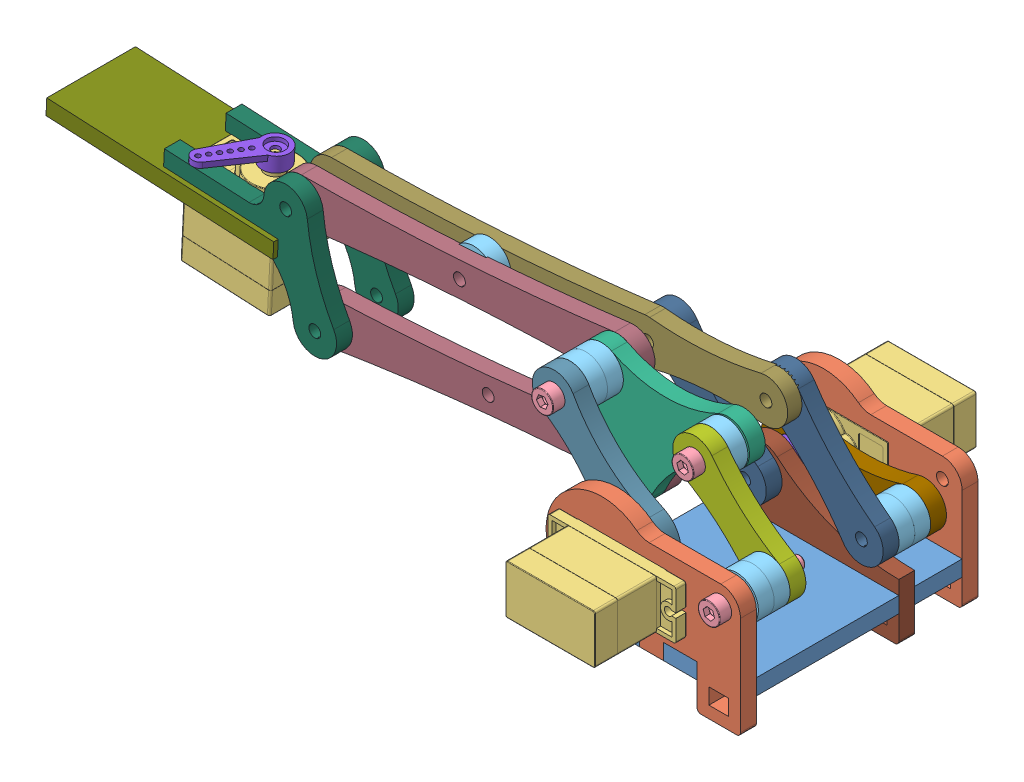
SolidWorks assembly Arm, configuration Default. Lengths in mm.
Overall size (197.53 59.85 96.4).
33 component instances, 16 part files, 77 mates.
Components (placement in the parent):
- Base (Finger Joint Connection)-1: Base (Finger Joint Connection) [Default] at (25.9477 4 37.3679) x (1 0 0) z (0 -1 0) size (45 60 4)
- Side Panel (Finger Joint Connection)-1: Side Panel (Finger Joint Connection) [Default] at (25.9477 4 93.3679) size (49.14 35.14 4)
- Side Panel (Finger Joint Connection)-2: Side Panel (Finger Joint Connection) [Default] at (25.9477 4 37.3679) size (49.14 35.14 4)
- microservoSG90-3: microservoSG90 [Default] at (41.0477 14 19.1679) x (1 0 0) z (0 -1 0) size (32.3 29.8 12.5)
- socket head cap screw_iso-3: socket head cap screw_iso [ISO 4762 M3 x 20 - 20N] at (65.9477 19 100.3679) x (0 0 -1) z (0.947312 0.320314 0) size (23 5.5 5.5)
- 4mm Spacer-2: 4mm Spacer [Default] at (65.9477 19 93.3679) x (0.6336 -0.773661 0) z (0.773661 0.6336 0) size (11 4 11)
- Stabilizer Triangle-1: Stabilizer Triangle [Default] at (22.5845 15.5383 72.9679) x (0.943404 0.331646 0) z (0 0 1) size (41 32.57 4)
- 4mm Spacer-3: 4mm Spacer [Default] at (15.4309 35.8875 84.9679) x (-0.98853 -0.151025 0) z (0.151025 -0.98853 0) size (11 4 11)
- socket head cap screw_iso-4: socket head cap screw_iso [ISO 4762 M3 x 16 - 16N] at (15.4309 35.8875 91.9679) x (0 0 -1) z (0.778189 0.62803 0) size (19 5.5 5.5)
- X-Link-1: X-Link [Default] at (65.9477 19 81.3679) x (0.666489 0.745515 0) z (0.745515 -0.666489 0) size (11 4 36)
- 4mm Spacer-4: 4mm Spacer [Default] at (65.9477 19 89.3679) x (0.6336 -0.773661 0) z (0.773661 0.6336 0) size (11 4 11)
- SG90 - Micro Servo 9g - Tower Pro.2-1: SG90 - Micro Servo 9g - Tower Pro.2 [Peça] at (35.9477 14 83.5679) x (0.767364 -0.641212 0) z (0.641212 0.767364 0) size (19.5 3.8 6.9)
- socket head cap screw_iso-5: socket head cap screw_iso [ISO 4762 M3 x 12 - 12N] at (47.3098 35.6622 88.3679) x (0 0 -1) z (0.947312 0.320314 0) size (15 5.5 5.5)
- 4mm Spacer-5: 4mm Spacer [Default] at (15.4309 35.8875 80.9679) x (0.983445 -0.181209 0) z (0.181209 0.983445 0) size (11 4 11)
- 4mm Spacer-6: 4mm Spacer [Default] at (47.3098 35.6622 81.3679) x (0.937465 0.34808 0) z (-0.34808 0.937465 0) size (11 4 11)
- Y-Servo Link-1: Y-Servo Link [Default] at (50.9155 14.982 45.7679) x (0.065468 -0.997855 0) z (0 0 1) size (15.2 43.1 4)
- Y-Link 1-1: Y-Link 1 [Default] at (65.8833 15.964 57.7679) x (0.729583 0.683893 0) z (0.683893 -0.729583 0) size (11 4 41)
- SG90 - Micro Servo 9g - Tower Pro.2-2: SG90 - Micro Servo 9g - Tower Pro.2 [Peça] at (35.9477 14 51.1679) x (-0.768689 0.639623 0) z (0.639623 0.768689 0) size (19.5 3.8 6.9)
- 4mm Spacer-7: 4mm Spacer [Default] at (65.8833 15.964 53.7679) x (0.985317 0.170736 0) z (-0.170736 0.985317 0) size (11 4 11)
- 4mm Spacer-8: 4mm Spacer [Default] at (65.8833 15.964 57.7679) x (0.265682 0.964061 0) z (-0.964061 0.265682 0) size (11 4 11)
- Centre Y link base connector-1: Centre Y link base connector [Default] at (25.9477 4 53.3679) size (45 27.5 4)
- Y-Link 1-2: Y-Link 1 [Default] at (35.9477 14 57.3679) x (0.729583 0.683893 0) z (0.683893 -0.729583 0) size (11 4 41)
- Y-long link-1: Y-long link [Default] at (45.3665 37.8515 61.3679) x (-0.065468 0.997855 0) z (0.997855 0.065468 0) size (11 4 121)
- X-long link-1: X-long link [Default] at (15.4309 35.8875 68.9679) x (-0.065468 0.997855 0) z (0.997855 0.065468 0) size (11 4 91)
- X-Servo Link-3: X-Servo Link [Default] at (25.6893 24.9437 84.9679) x (0.729583 0.683893 0) z (0 0 1) size (15.2 43.1 4)
- microservoSG90-4: microservoSG90 [Default] at (41.0477 14 115.5679) x (1 0 0) z (0 1 0) size (32.3 29.8 12.5)
- 4mm Spacer-9: 4mm Spacer [Default] at (-24.4833 33.2687 69.3679) x (-0.98853 -0.151025 0) z (0.151025 -0.98853 0) size (11 4 11)
- X-long link-2: X-long link [Default] at (22.5845 15.5383 68.9679) x (-0.098515 0.995136 0) z (0.995136 0.098515 0) size (11 4 91)
- Horizontalizer Connector-1: Horizontalizer Connector [Default] at (-64.3975 30.65 76.9679) x (-0.998775 0.049489 0) z (0 0 -1) size (44.5 33.6 4)
- Horizontalizer Connector-2: Horizontalizer Connector [Default] at (-64.3975 30.65 61.3679) x (-0.998775 0.049489 0) z (0 0 -1) size (44.5 33.6 4)
- Gripper Servo Mount-1: Gripper Servo Mount [Default] at (-71.2656 23.381 73.1014) x (-0.998775 0.049489 0) z (0 0 1) size (57.42 4 22.42)
- microservoSG90-5: microservoSG90 [Default] at (-83.6504 1.7674 66.9014) x (-0.998775 0.049489 0) z (0 0 -1) size (32.3 29.8 12.5)
- SG90 - Micro Servo 9g - Tower Pro.2-3: SG90 - Micro Servo 9g - Tower Pro.2 [Peça] at (-76.973 33.4758 66.9014) x (0.486267 -0.024095 -0.873478) z (0.872408 -0.043228 0.486863) size (19.5 3.8 6.9)
Mates (geometry in assembly coordinates):
- Coincident2: coincident anti-aligned: plane of Base (Finger Joint Connection)-1 through (25.9477 0 37.3679) normal (0 -1 0)
- Coincident3: coincident anti-aligned: plane of Base (Finger Joint Connection)-1 through (36.9477 0 37.3679) normal (-1 0 0); plane of Side Panel (Finger Joint Connection)-1 through (36.9477 4 97.3679) normal (1 0 0)
- Coincident4: coincident anti-aligned: plane of Base (Finger Joint Connection)-1 through (25.9477 4 37.3679) normal (0 1 0); plane of Side Panel (Finger Joint Connection)-1 through (25.9477 4 97.3679) normal (0 -1 0)
- Coincident5: coincident anti-aligned: line of Base (Finger Joint Connection)-1 through (36.9477 0 97.3679) axis (0 1 0); line of Side Panel (Finger Joint Connection)-1 through (36.9477 4 97.3679) axis (0 -1 0)
- Coincident6: coincident aligned: plane of Base (Finger Joint Connection)-1 through (25.9477 0 37.3679) normal (-1 0 0); plane of Side Panel (Finger Joint Connection)-2 through (25.9477 4 41.3679) normal (-1 0 0)
- Coincident7: coincident aligned: plane of Base (Finger Joint Connection)-1 through (25.9477 0 37.3679) normal (0 0 -1); plane of Side Panel (Finger Joint Connection)-2 through (25.9477 4 37.3679) normal (0 0 -1)
- Coincident9: coincident anti-aligned: line of Base (Finger Joint Connection)-1 through (45.4477 4 37.3679) axis (0 0 1); line of Side Panel (Finger Joint Connection)-2 through (45.4477 4 41.3679) axis (0 0 -1)
- Coincident14: coincident anti-aligned: plane of Side Panel (Finger Joint Connection)-2 through (25.9477 7.8 41.3679) normal (0 1 0); plane of microservoSG90-3 through (29.7477 7.8 34.7679) normal (0 -1 0)
- Coincident15: coincident anti-aligned: plane of Side Panel (Finger Joint Connection)-2 through (29.7477 4 41.3679) normal (1 0 0); plane of microservoSG90-3 through (29.7477 20.2 41.4679) normal (-1 0 0)
- Coincident18: coincident anti-aligned: plane of Side Panel (Finger Joint Connection)-2 through (25.9477 4 37.3679) normal (0 0 -1); plane of microservoSG90-3 through (41.0477 14 37.3679) normal (0 0 1)
- Concentric11: concentric anti-aligned: cylinder of Side Panel (Finger Joint Connection)-1 through (65.9477 19 97.3679) axis (0 0 -1) radius 1.5; cylinder of socket head cap screw_iso-3 through (65.9477 19 132.1179) axis (0 0 1) radius 2.75
- Coincident19: coincident anti-aligned: plane of Side Panel (Finger Joint Connection)-1 through (25.9477 4 97.3679) normal (0 0 1); plane of socket head cap screw_iso-3 through (65.0668 21.6051 97.3679) normal (0 0 -1)
- Concentric14: concentric aligned: cylinder of socket head cap screw_iso-3 through (65.9477 19 132.1179) axis (0 0 1) radius 1.5; cylinder of 4mm Spacer-2 through (65.9477 19 89.3679) axis (0 0 1) radius 1.5
- Coincident22: coincident anti-aligned: plane of Side Panel (Finger Joint Connection)-1 through (25.9477 4 93.3679) normal (0 0 -1); plane of 4mm Spacer-2 through (65.9477 19 93.3679) normal (0 0 1)
- Concentric18: concentric anti-aligned: cylinder of Stabilizer Triangle-1 through (15.4309 35.8875 76.9679) axis (0 0 -1) radius 1.5; cylinder of socket head cap screw_iso-4 through (15.4309 35.8875 123.7179) axis (0 0 1) radius 1.5
- Concentric19: concentric anti-aligned: cylinder of socket head cap screw_iso-3 through (65.9477 19 132.1179) axis (0 0 1) radius 1.5; cylinder of X-Link-1 through (65.9477 19 85.3679) axis (0 0 -1) radius 1.5
- Coincident27: coincident anti-aligned: plane of X-Link-1 through (40.6687 0.1012 85.3679) normal (0 0 1); plane of 4mm Spacer-4 through (65.9477 19 85.3679) normal (0 0 -1)
- Concentric21: concentric aligned: cylinder of socket head cap screw_iso-3 through (65.9477 19 132.1179) axis (0 0 1) radius 1.5; cylinder of 4mm Spacer-4 through (65.9477 19 85.3679) axis (0 0 1) radius 1.5
- Coincident30: coincident anti-aligned: plane of X-Link-1 through (40.6687 0.1012 85.3679) normal (0 0 1); plane of socket head cap screw_iso-5 through (46.429 38.2673 85.3679) normal (0 0 -1)
- Concentric23: concentric anti-aligned: cylinder of X-Link-1 through (47.3098 35.6622 85.3679) axis (0 0 -1) radius 1.5; cylinder of socket head cap screw_iso-5 through (47.3098 35.6622 120.1179) axis (0 0 1) radius 1.5
- Coincident33: coincident anti-aligned: circle of 4mm Spacer-3; cylinder of socket head cap screw_iso-4 through (15.4309 35.8875 123.7179) axis (0 0 1) radius 1.5
- Coincident35: coincident anti-aligned: plane of 4mm Spacer-3 through (15.4309 35.8875 80.9679) normal (0 0 -1); plane of 4mm Spacer-5 through (15.4309 35.8875 80.9679) normal (0 0 1)
- Concentric24: concentric aligned: cylinder of socket head cap screw_iso-4 through (15.4309 35.8875 123.7179) axis (0 0 1) radius 1.5; cylinder of 4mm Spacer-5 through (15.4309 35.8875 76.9679) axis (0 0 1) radius 1.5
- Coincident36: coincident anti-aligned: plane of Stabilizer Triangle-1 through (22.5845 15.5383 76.9679) normal (0 0 1); plane of 4mm Spacer-5 through (15.4309 35.8875 76.9679) normal (0 0 -1)
- Concentric25: concentric anti-aligned: cylinder of Stabilizer Triangle-1 through (47.3098 35.6622 76.9679) axis (0 0 -1) radius 1.5; cylinder of socket head cap screw_iso-5 through (47.3098 35.6622 120.1179) axis (0 0 1) radius 1.5
- Coincident37: coincident aligned: plane of 4mm Spacer-2 through (65.9477 19 89.3679) normal (0 0 -1); plane of 4mm Spacer-4
- Concentric26: concentric aligned: cylinder of socket head cap screw_iso-5 through (47.3098 35.6622 120.1179) axis (0 0 1) radius 1.5; cylinder of 4mm Spacer-6 through (47.3098 35.6622 77.3679) axis (0 0 1) radius 1.5
- Coincident38: coincident anti-aligned: plane of X-Link-1 through (40.6687 0.1012 81.3679) normal (0 0 -1); plane of 4mm Spacer-6 through (47.3098 35.6622 81.3679) normal (0 0 1)
- Concentric27: concentric aligned: cylinder of microservoSG90-3 through (35.9477 14 48.9679) axis (0 0 -1) radius 2.45; cylinder of Y-Servo Link-1 through (35.9477 14 49.7679) axis (0 0 -1) radius 3.6
- Coincident40: coincident anti-aligned: plane of microservoSG90-3 through (41.6977 14 45.7679) normal (0 0 1); plane of Y-Servo Link-1 through (50.9155 14.982 45.7679) normal (0 0 -1)
- Concentric29: concentric anti-aligned: cylinder of microservoSG90-3 through (35.9477 14 48.9679) axis (0 0 -1) radius 0.8; circle of SG90 - Micro Servo 9g - Tower Pro.2-2
- Coincident41: coincident anti-aligned: plane of Y-Servo Link-1 through (50.9155 14.982 49.7679) normal (0 0 1); plane of SG90 - Micro Servo 9g - Tower Pro.2-2 through (35.9477 14 49.7679) normal (0 0 -1)
- Tangent6: tangent anti-aligned: plane of Y-Servo Link-1; plane of SG90 - Micro Servo 9g - Tower Pro.2-2 through (39.3408 14.6241 49.7679) normal (0.680611 0.732645 0)
- Concentric30: concentric aligned: cylinder of Y-Servo Link-1 through (65.8833 15.964 49.7679) axis (0 0 -1) radius 1.5; cylinder of Y-Link 1-1 through (65.8833 15.964 61.7679) axis (0 0 -1) radius 1.5
- Concentric31: concentric anti-aligned: cylinder of Y-Link 1-1 through (65.8833 15.964 61.7679) axis (0 0 -1) radius 1.5; cylinder of 4mm Spacer-7 through (65.8833 15.964 49.7679) axis (0 0 1) radius 1.5
- Coincident43: coincident anti-aligned: plane of Y-Servo Link-1 through (50.9155 14.982 49.7679) normal (0 0 1); plane of 4mm Spacer-7 through (65.8833 15.964 49.7679) normal (0 0 -1)
- Coincident44: coincident anti-aligned: plane of 4mm Spacer-7 through (65.8833 15.964 53.7679) normal (0 0 1); plane of 4mm Spacer-8 through (65.8833 15.964 53.7679) normal (0 0 -1)
- Concentric33: concentric aligned: cylinder of 4mm Spacer-7 through (65.8833 15.964 49.7679) axis (0 0 1) radius 1.5; cylinder of 4mm Spacer-8 through (65.8833 15.964 53.7679) axis (0 0 1) radius 1.5
- Coincident45: coincident anti-aligned: plane of Y-Link 1-1 through (28.1509 -9.1255 57.7679) normal (0 0 -1); plane of 4mm Spacer-8 through (65.8833 15.964 57.7679) normal (0 0 1)
- Concentric34: concentric aligned: cylinder of Centre Y link base connector-1 through (35.9477 14 57.3679) axis (0 0 -1) radius 1.5; cylinder of Y-Link 1-2 through (35.9477 14 61.3679) axis (0 0 -1) radius 1.5
- Coincident49: coincident anti-aligned: plane of Centre Y link base connector-1 through (25.9477 4 57.3679) normal (0 0 1); plane of Y-Link 1-2 through (-1.7847 -11.0896 57.3679) normal (0 0 -1)
- Coincident51: coincident anti-aligned: plane of Y-Link 1-2 through (-1.7847 -11.0896 61.3679) normal (0 0 1); plane of Y-long link-1 through (-23.511 -287.0423 61.3679) normal (0 0 -1)
- Concentric36: concentric aligned: cylinder of Y-Link 1-2 through (15.4309 35.8875 61.3679) axis (0 0 -1) radius 1.5; cylinder of Y-long link-1 through (15.4309 35.8875 65.3679) axis (0 0 -1) radius 1.5
- Coincident52: coincident anti-aligned: circle of Y-Link 1-1; cylinder of Y-long link-1 through (45.3665 37.8515 65.3679) axis (0 0 -1) radius 1.5
- Concentric38: concentric aligned: circle of SG90 - Micro Servo 9g - Tower Pro.2-2; cylinder of Centre Y link base connector-1 through (35.9477 14 57.3679) axis (0 0 -1) radius 1.5
- Concentric39: concentric aligned: cylinder of Stabilizer Triangle-1 through (15.4309 35.8875 76.9679) axis (0 0 -1) radius 1.5; cylinder of Y-Link 1-2 through (15.4309 35.8875 61.3679) axis (0 0 -1) radius 1.5
- Coincident57: coincident anti-aligned: plane of Base (Finger Joint Connection)-1 through (25.9477 4 37.3679) normal (0 1 0); plane of Centre Y link base connector-1 through (25.9477 4 57.3679) normal (0 -1 0)
- Coincident58: coincident anti-aligned: plane of Base (Finger Joint Connection)-1 through (25.9477 0 57.3679) normal (0 0 -1); plane of Centre Y link base connector-1 through (25.9477 4 57.3679) normal (0 0 1)
- Coincident59: coincident anti-aligned: plane of Side Panel (Finger Joint Connection)-1 through (25.9477 20.2 97.3679) normal (0 -1 0); plane of microservoSG90-4 through (29.7477 20.2 99.9679) normal (0 1 0)
- Coincident60: coincident anti-aligned: plane of Side Panel (Finger Joint Connection)-1 through (29.7477 4 97.3679) normal (1 0 0); plane of microservoSG90-4 through (29.7477 7.8 93.2679) normal (-1 0 0)
- Coincident61: coincident anti-aligned: plane of Side Panel (Finger Joint Connection)-1 through (25.9477 4 97.3679) normal (0 0 1); plane of microservoSG90-4 through (41.0477 14 97.3679) normal (0 0 -1)
- Concentric44: concentric anti-aligned: cylinder of X-Servo Link-3 through (35.9477 14 88.9679) axis (0 0 -1) radius 3.6; cylinder of microservoSG90-4 through (35.9477 14 85.7679) axis (0 0 1) radius 2.45
- Coincident62: coincident anti-aligned: plane of X-Servo Link-3 through (25.6893 24.9437 88.9679) normal (0 0 1); plane of microservoSG90-4 through (41.6977 14 88.9679) normal (0 0 -1)
- Concentric45: concentric anti-aligned: cylinder of socket head cap screw_iso-4 through (15.4309 35.8875 123.7179) axis (0 0 1) radius 1.5; cylinder of X-Servo Link-3 through (15.4309 35.8875 88.9679) axis (0 0 -1) radius 1.5
- Concentric46: concentric aligned: circle of Stabilizer Triangle-1; circle of X-long link-1
- Coincident66: coincident anti-aligned: plane of 4mm Spacer-3 through (15.4309 35.8875 84.9679) normal (0 0 1); plane of X-Servo Link-3 through (25.6893 24.9437 84.9679) normal (0 0 -1)
- Coincident67: coincident anti-aligned: plane of Stabilizer Triangle-1 through (22.5845 15.5383 72.9679) normal (0 0 -1); plane of X-long link-1 through (16.4032 -284.4235 72.9679) normal (0 0 1)
- Concentric47: concentric aligned: cylinder of Y-long link-1 through (-66.342 671.2721 65.3679) axis (0 0 -1) radius 635.125; cylinder of X-long link-1 through (-66.342 671.2721 72.9679) axis (0 0 -1) radius 635.125
- Concentric48: concentric aligned: cylinder of SG90 - Micro Servo 9g - Tower Pro.2-1 through (35.9477 14 84.9679) axis (0 0 -1) radius 3.45; cylinder of X-Servo Link-3 through (35.9477 14 88.9679) axis (0 0 -1) radius 3.6
- Coincident68: coincident anti-aligned: plane of SG90 - Micro Servo 9g - Tower Pro.2-1 through (35.9477 14 84.9679) normal (0 0 1); plane of X-Servo Link-3 through (25.6893 24.9437 84.9679) normal (0 0 -1)
- Tangent7: tangent: plane of SG90 - Micro Servo 9g - Tower Pro.2-1 through (23.802 21.5466 84.9679) normal (-0.682125 -0.731236 0); circle of X-Servo Link-3
- Concentric49: concentric anti-aligned: cylinder of X-long link-1 through (-24.4833 33.2687 72.9679) axis (0 0 -1) radius 1.5; cylinder of 4mm Spacer-9 through (-24.4833 33.2687 65.3679) axis (0 0 1) radius 1.5
- Coincident70: coincident anti-aligned: plane of Y-long link-1 through (-23.511 -287.0423 65.3679) normal (0 0 1); plane of 4mm Spacer-9
- Concentric50: concentric aligned: cylinder of Stabilizer Triangle-1 through (22.5845 15.5383 76.9679) axis (0 0 -1) radius 1.5; cylinder of X-long link-2 through (22.5845 15.5383 72.9679) axis (0 0 -1) radius 1.5
- Coincident71: coincident anti-aligned: plane of Stabilizer Triangle-1 through (22.5845 15.5383 72.9679) normal (0 0 -1); plane of X-long link-2 through (34.1758 -304.5645 72.9679) normal (0 0 1)
- Coincident72: coincident anti-aligned: circle of X-long link-1; circle of Horizontalizer Connector-1
- Concentric52: concentric anti-aligned: cylinder of X-long link-2 through (-57.0263 7.6571 72.9679) axis (0 0 -1) radius 1.5; cylinder of Horizontalizer Connector-1 through (-57.0263 7.6571 72.9679) axis (0 0 1) radius 1.5
- Coincident73: coincident aligned: circle of Y-long link-1; cylinder of Horizontalizer Connector-2 through (-64.3975 30.65 57.3679) axis (0 0 1) radius 1.5
- Coincident74: coincident anti-aligned: plane of Y-long link-1 through (-23.511 -287.0423 61.3679) normal (0 0 -1); plane of Horizontalizer Connector-2 through (-64.3975 30.65 61.3679) normal (0 0 1)
- Concentric53: concentric aligned: cylinder of Horizontalizer Connector-1 through (-57.0263 7.6571 72.9679) axis (0 0 1) radius 1.5; cylinder of Horizontalizer Connector-2 through (-57.0263 7.6571 57.3679) axis (0 0 1) radius 1.5
- Coincident75: coincident anti-aligned: plane of Horizontalizer Connector-1 through (-66.2718 23.1336 82.9679) normal (-0.998775 0.049489 0); plane of Gripper Servo Mount-1 through (-66.4697 19.1385 55.6814) normal (0.998775 -0.049489 0)
- Coincident77: coincident anti-aligned: plane of Horizontalizer Connector-1 through (-64.7736 23.0593 72.9679) normal (-0.049489 -0.998775 0); plane of Gripper Servo Mount-1 through (-71.2656 23.381 73.1014) normal (0.049489 0.998775 0)
- Coincident78: coincident anti-aligned: plane of Gripper Servo Mount-1 through (-71.4636 19.3859 73.1014) normal (-0.998775 0.049489 0); plane of microservoSG90-5 through (-71.2607 23.4809 73.1014) normal (0.998775 -0.049489 0)
- Coincident79: coincident anti-aligned: plane of Gripper Servo Mount-1 through (-71.4636 19.3859 73.1014) normal (0 0 -1); plane of microservoSG90-5 through (-71.5923 16.7891 73.1014) normal (0 0 1)
- Coincident80: coincident anti-aligned: plane of Gripper Servo Mount-1 through (-71.4636 19.3859 73.1014) normal (-0.049489 -0.998775 0); plane of microservoSG90-5 through (-82.7497 19.9451 66.9014) normal (0.049489 0.998775 0)
- Concentric54: concentric anti-aligned: cylinder of microservoSG90-5 through (-77.0819 31.2785 66.9014) axis (-0.049489 -0.998775 0) radius 2.45; cylinder of SG90 - Micro Servo 9g - Tower Pro.2-3 through (-76.973 33.4758 66.9014) axis (0.049489 0.998775 0) radius 1.05
- Distance1: distance = 4 mm anti-aligned: plane of SG90 - Micro Servo 9g - Tower Pro.2-3 through (-77.0423 32.0776 66.9014) normal (-0.049489 -0.998775 0); plane of microservoSG90-5 through (-82.9832 28.367 66.9014) normal (0.049489 0.998775 0)
